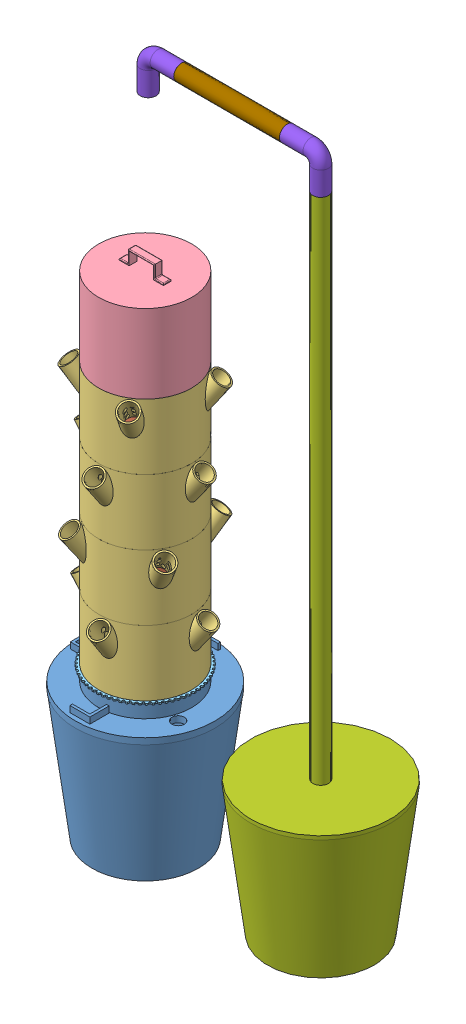
SolidWorks assembly Assem1, configuration Default. Lengths in mm.
Overall size (2116.8 4425.91 1123.61).
13 component instances, 9 part files, 12 mates.
Components (placement in the parent):
- ember-1: ember [Default] at (345.0936 394.0169 811.6244) size (899.83 976.37 899.83)
- Pipakecil-3: Pipakecil [Default] at (340.8938 921.8608 800.7788) x (0.00527 0 0.999986) z (0 1 0) size (579.48 579.48 2373)
- lobang-1: lobang [Default] at (345.0936 991.0169 811.6244) x (0.988827 0 -0.149067) z (0 1 0) size (813.64 813.64 422)
- lobang-2: lobang [Default] at (345.0936 1413.0169 811.6244) x (0.506432 0 -0.86228) z (0 1 0) size (813.64 813.64 422)
- lobang-3: lobang [Default] at (345.0936 1835.0169 811.6244) x (0.997277 0 -0.073753) z (0 1 0) size (813.64 813.64 422)
- lobang-5: lobang [Default] at (345.0936 2257.0169 811.6244) x (0.53809 0 0.842888) z (0 1 0) size (813.64 813.64 422)
- penutup-1: penutup [Default] at (345.0936 2921.0169 811.6244) x (-1 0 0) z (0 -1 0) size (600 600 597)
- gear-1: gear [Default] at (345.0936 974.0169 811.6244) x (-0.009812 0 -0.999952) z (0 -1 0) size (640.05 639.87 10)
- Pompa-1: Pompa [Default] at (348.2762 570.221 858.6567) x (0.999993 0 0.00366) z (0.000679 0.982667 -0.18538) size (252 150 142)
- ember2-1: ember2 [Default] at (1449.7006 43.1439 782.695) size (900.78 4159.21 900.78)
- Lbow-1: Lbow [Default] at (1449.7006 4152.3559 782.695) size (266.7 266.7 101.6)
- Pipatambahan-1: Pipatambahan [Default] at (1233.8006 4368.2559 782.695) x (0 0 -1) z (-1 0 0) size (101.6 101.6 682.75)
- Lbow-2: Lbow [Default] at (335.1486 4152.3559 782.695) x (-1 0 0) z (0 0 -1) size (266.7 266.7 101.6)
Mates (geometry in assembly coordinates):
- Coincident8: coincident aligned: circle of lobang-1; circle of lobang-2
- Coincident9: coincident aligned: circle of lobang-2; circle of lobang-3
- Coincident10: coincident aligned: circle of lobang-3; circle of lobang-5
- Coincident11: coincident anti-aligned: circle of lobang-5; circle of part1-1
- Coincident12: coincident anti-aligned: plane of ember-1 through (345.0936 974.0169 811.6244) normal (0 1 0); plane of lobang-1 through (345.0936 974.0169 811.6244) normal (0 -1 0)
- Coincident15: coincident anti-aligned: plane of ember-1 through (345.0936 974.0169 811.6244) normal (0 1 0); plane of lobang-1 through (345.0936 974.0169 811.6244) normal (0 -1 0)
- Coincident17: coincident anti-aligned: circle of ember-1; circle of gear-1
- Coincident18: coincident anti-aligned: circle of lobang-1; circle of gear-1
- Tangent1: tangent anti-aligned: plane of Pipakecil-3 through (340.8938 648.8608 800.7788) normal (0 -1 0); cylinder of Pompa-1 through (313.4107 610.8608 821.8335) axis (0.999993 0 0.00366) radius 38
- Coincident20: coincident aligned: circle of ember2-1; circle of Part2-1
- Coincident21: coincident aligned: circle of Part2-1; circle of Part3-1
- Coincident22: coincident anti-aligned: circle of Part3-1; circle of Part2-2
